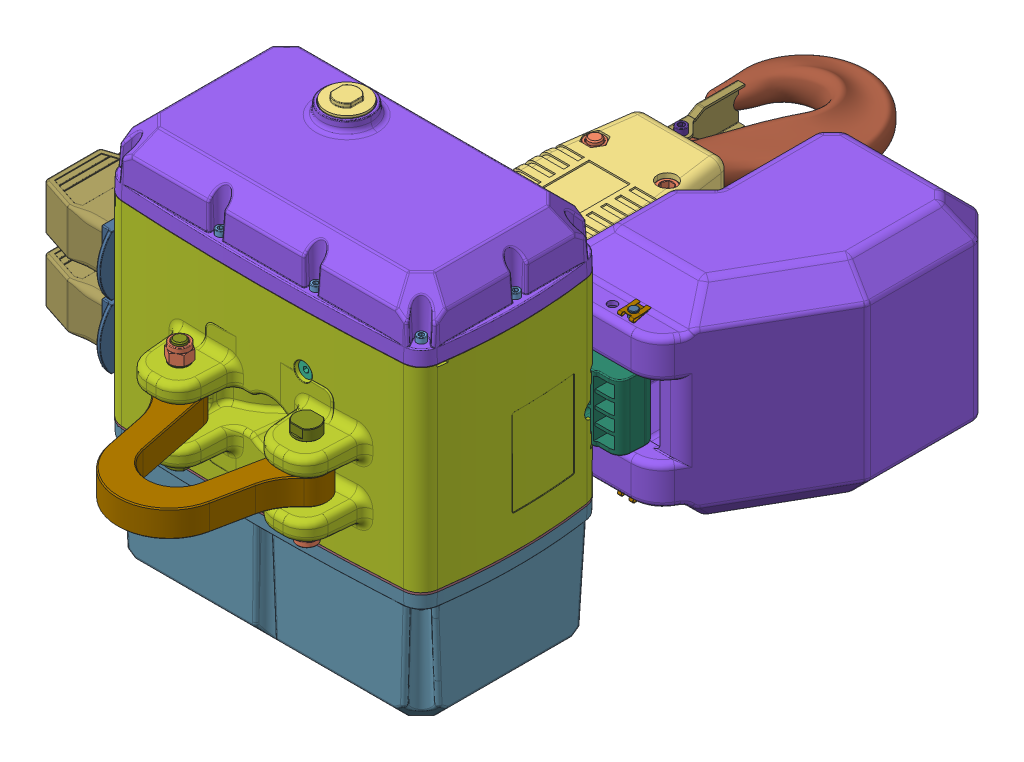
SolidWorks assembly NCH2072-2000kg, configuration 默认. Lengths in mm.
Overall size (525.49 383 710.03).
102 component instances, 45 part files, 0 mates.
Components (placement in the parent):
- N120411-0000018_A-1: N120411-0000018_A [默认] at origin size (432.61 383 254.47)
  - N120411-0000038_A-1: N120411-0000038_A [默认] at (227 0 0) x (-1 0 0) z (0 0 1) size (312 295.03 232.39)
    - N010122-0000197_A-2-1: N010122-0000197_A-2 [默认] at (207 -124.7 87.75) x (1 0 0) z (0 -1 0) size (8.5 8.5 30.21)
    - N010122-0000197_A-2-2: N010122-0000197_A-2 [默认] at (25 -124.7 -65.75) x (0 0 -1) z (0 -1 0) size (8.5 8.5 30.21)
    - N010122-0000197_A-2-3: N010122-0000197_A-2 [默认] at (25 -124.7 95.25) x (0 0 -1) z (0 -1 0) size (8.5 8.5 30.21)
    - N010122-0000197_A-2-4: N010122-0000197_A-2 [默认] at (-67 -124.7 -58.25) x (1 0 0) z (0 -1 0) size (8.5 8.5 30.21)
    - N010122-0000197_A-2-5: N010122-0000197_A-2 [默认] at (-67 -124.7 87.75) x (-1 0 0) z (0 -1 0) size (8.5 8.5 30.21)
    - N010122-0000197_A-2-6: N010122-0000197_A-2 [默认] at (207 -124.7 -58.25) x (0 0 -1) z (0 -1 0) size (8.5 8.5 30.21)
    - N010122-0000197_A-2-7: N010122-0000197_A-2 [默认] at (115 -124.7 -65.75) x (0 0 -1) z (0 -1 0) size (8.5 8.5 30.21)
    - N010122-0000197_A-2-8: N010122-0000197_A-2 [默认] at (-75 -124.7 7.0181) x (0 0 -1) z (0 -1 0) size (8.5 8.5 30.21)
    - N010122-0000197_A-2-9: N010122-0000197_A-2 [默认] at (215 -124.7 7.05) x (-1 0 0) z (0 -1 0) size (8.5 8.5 30.21)
    - N010122-0000197_A-2-10: N010122-0000197_A-2 [默认] at (115 -124.7 95.25) x (0 0 -1) z (0 -1 0) size (8.5 8.5 30.21)
    - N090501-0000042-1: N090501-0000042 [默认] at (70 -110.2 14.75) x (1 0 0) z (0 -1 0) size (310 180 0.5)
    - N090501-0000029-2-1: N090501-0000029-2 [默认] at (109.28 -179.2 -18.11) x (0 0 -1) z (1 0 0) size (39 14 39)
    - N090501-0000045-1: N090501-0000045 [默认] at (0 0 6.75) x (0 0 -1) z (1 0 0) size (51.5 30.1 103)
    - N090501-0000034-2-1: N090501-0000034-2 [默认] at (133 0 104.75) x (0 0 -1) z (-1 0 0) size (9 16 16)
    - N090501-0000034-2-2: N090501-0000034-2 [默认] at (133 55 104.75) x (0 0 -1) z (-1 0 0) size (9 16 16)
    - N010153-0000021-2-1: N010153-0000021-2 [默认] at (28 -60.2 96.65) x (0 0 -1) z (0.999621 -0.02754 0) size (11 14 14)
    - N090501-0000040-1: N090501-0000040 [默认] at (0 -96.2 6.75) x (1 0 0) z (0 -1 0) size (312 232.39 220.06)
    - N090501-0000041-1: N090501-0000041 [默认] at (70 -110.7 14.75) x (1 0 0) z (0 -1 0) size (310 180 68.75)
  - N120411-0000037_A-2-1: N120411-0000037_A-2 [默认] at (-13.5 19.2 24.25) x (0 0 -1) z (-1 0 0) size (115.15 58 102.79)
    - N080101-0000427-2-1: N080101-0000427-2 [默认] at (0 0 -13.5) x (-1 0 0) z (0 0 1) size (93 58 27)
    - N080101-0000426-2-1: N080101-0000426-2 [默认] at (-14 0 13.5) x (-1 0 0) z (0 1 0) size (48.06 27 56.06)
    - N080101-0000426-2-2: N080101-0000426-2 [默认] at (14 0 13.5) x (1 0 0) z (0 -1 0) size (48.06 27 56.06)
    - N080101-0000428-2-1: N080101-0000428-2 [默认] at (23.1007 0 65.4698) x (0.950157 0 0.31177) z (0.31177 0 -0.950157) size (35 33.1 27.16)
    - N080101-0000430-2-1: N080101-0000430-2 [默认] at (0.0003 0 33.5003) x (0 0 1) z (0 -1 0) size (75 73.68 56)
  - N120411-0000037_A-2-2: N120411-0000037_A-2 [默认] at (-13.5 -40.8 24.25) x (0 0 -1) z (-1 0 0) size (115.15 58 102.79)
    - N080101-0000427-2-1: N080101-0000427-2 [默认] at (0 0 -13.5) x (-1 0 0) z (0 0 1) size (93 58 27)
    - N080101-0000426-2-1: N080101-0000426-2 [默认] at (-14 0 13.5) x (-1 0 0) z (0 1 0) size (48.06 27 56.06)
    - N080101-0000426-2-2: N080101-0000426-2 [默认] at (14 0 13.5) x (1 0 0) z (0 -1 0) size (48.06 27 56.06)
    - N080101-0000428-2-1: N080101-0000428-2 [默认] at (23.1007 0 65.4698) x (0.950157 0 0.31177) z (0.31177 0 -0.950157) size (35 33.1 27.16)
    - N080101-0000430-2-1: N080101-0000430-2 [默认] at (0.0003 0 33.5003) x (0 0 1) z (0 -1 0) size (75 73.68 56)
  - N090501-0000044-1: N090501-0000044 [默认] at (157 -75.8 14.75) x (1 0 0) z (0 1 0) size (310 180 8)
  - N090501-0000043-1: N090501-0000043 [默认] at (157 -75.8 14.75) x (-1 0 0) z (0 1 0) size (310 180.63 122.55)
  - N090501-0000046-1: N090501-0000046 [默认] at (238.4113 0 -68.99) x (0 1 0) z (0 0 -1) size (62.8 182.79 104.72)
  - N090501-0000047-1: N090501-0000047 [默认] at (107 -47.25 128.75) x (-1 0 0) z (0 1 0) size (23.09 23.09 101)
  - N090501-0000047-2: N090501-0000047 [默认] at (227 47.25 128.75) x (0 0 -1) z (0 -1 0) size (23.09 23.09 101)
  - N080101-0000401-2-1: N080101-0000401-2 [默认] at (272.5252 -24.94 -81.04) x (1 0 0) z (0 1 0) size (20 18.9 6.45)
  - N080101-0000401-2-2: N080101-0000401-2 [默认] at (191.7884 -24.94 -70.94) x (1 0 0) z (0 1 0) size (20 18.9 6.45)
  - N010302-0000058-2-1: N010302-0000058-2 [默认] at (186.8531 -16.9523 -71.84) x (0 -1 0) z (-0.268551 0 0.963266) size (14 2.5 2.5)
  - N010302-0000058-2-2: N010302-0000058-2 [默认] at (277.2152 -16.9784 -81.94) x (0 -1 0) z (-0.268551 0 0.963266) size (14 2.5 2.5)
  - N010302-0000058-2-3: N010302-0000058-2 [默认] at (267.5899 -16.9523 -81.94) x (0 -1 0) z (-0.268551 0 0.963266) size (14 2.5 2.5)
  - N010302-0000058-2-4: N010302-0000058-2 [默认] at (196.4784 -16.9784 -71.84) x (0 -1 0) z (-0.268551 0 0.963266) size (14 2.5 2.5)
  - Washer_GBIT_95_2002_5.0_v12.00-1: Washer_GBIT_95_2002_5.0_v12.00 [默认] at (294.4484 24.24 -82.445) x (0 -1 0) z (0 0 -1) size (10 10 1)
  - Washer_GBIT_95_2002_5.0_v12.00-2: Washer_GBIT_95_2002_5.0_v12.00 [默认] at (294.4484 -24.24 -82.445) x (-1 0 0) z (0 0 -1) size (10 10 1)
  - Nut_GBIT_889.1_2000_M12_v12.00-1: Nut_GBIT_889.1_2000_M12_v12.00 [默认] at (227 -36.75 128.75) x (0 0 -1) z (0 -1 0) size (20.78 18 14.9)
  - Nut_GBIT_889.1_2000_M12_v12.00-2: Nut_GBIT_889.1_2000_M12_v12.00 [默认] at (107 36.75 128.75) x (0 0 1) z (0 1 0) size (20.78 18 14.9)
  - Washer_GBIT_96_1985_6.0_v12.00-2-1: Washer_GBIT_96_1985_6.0_v12.00-2 [默认] at (8.5 19.2 -58.25) x (0 1 0) z (-1 0 0) size (18 18 1.6)
  - N010122-0000201-2-1: N010122-0000201-2 [默认] at (294.4484 24.24 -83.445) x (0 0 1) z (1 0 0) size (35 8.5 8.5)
  - N010122-0000201-2-2: N010122-0000201-2 [默认] at (294.4484 -24.24 -83.445) x (0 0 1) z (1 0 0) size (35 8.5 8.5)
  - N010108-0000011-2-1: N010108-0000011-2 [默认] at (7 -24.8 -17.25) x (0 0 1) z (0 -1 0) size (7 15.13 7)
  - N010108-0000011-2-2: N010108-0000011-2 [默认] at (7 -24.8 65.75) x (0 0 1) z (0 -1 0) size (7 15.13 7)
  - N010108-0000011-2-3: N010108-0000011-2 [默认] at (7 -56.8 65.75) x (0 0 1) z (0 -1 0) size (7 15.13 7)
  - N010108-0000011-2-4: N010108-0000011-2 [默认] at (7 35.2 -17.25) x (0 0 1) z (0 -1 0) size (7 15.13 7)
  - N010108-0000011-2-5: N010108-0000011-2 [默认] at (7 35.2 65.75) x (0 0 1) z (0 -1 0) size (7 15.13 7)
  - N010108-0000011-2-6: N010108-0000011-2 [默认] at (7 -56.8 -17.25) x (0 0 1) z (0 -1 0) size (7 15.13 7)
  - N010108-0000011-2-7: N010108-0000011-2 [默认] at (7 3.2 65.75) x (0 0 1) z (0 -1 0) size (7 15.13 7)
  - N010108-0000011-2-8: N010108-0000011-2 [默认] at (7 3.2 -17.25) x (0 0 1) z (0 -1 0) size (7 15.13 7)
  - N010122-0000129_A-2-1: N010122-0000129_A-2 [默认] at (6.9 19.2 -58.25) x (0 -1 0) z (-1 0 0) size (10 10 16.26)
  - N010122-0000197_A-2-1: N010122-0000197_A-2 [默认] at (20 -87.8 -58.25) x (0 0 -1) z (0 -1 0) size (8.5 8.5 30.21)
  - N010122-0000197_A-2-2: N010122-0000197_A-2 [默认] at (20 -87.8 87.75) x (0 0 -1) z (0 -1 0) size (8.5 8.5 30.21)
  - N010122-0000197_A-2-3: N010122-0000197_A-2 [默认] at (294 -87.8 -58.25) x (1 0 0) z (0 -1 0) size (8.5 8.5 30.21)
  - N010122-0000197_A-2-4: N010122-0000197_A-2 [默认] at (157 -87.8 95.25) x (1 0 0) z (0 -1 0) size (8.5 8.5 30.21)
  - N010122-0000197_A-2-5: N010122-0000197_A-2 [默认] at (294 -87.8 87.75) x (0 0 1) z (0 -1 0) size (8.5 8.5 30.21)
  - N010122-0000197_A-2-6: N010122-0000197_A-2 [默认] at (157 -87.8 -65.75) x (1 0 0) z (0 -1 0) size (8.5 8.5 30.21)
  - N010122-0000126_A-1: N010122-0000126_A [默认] at (161.1284 22.22 -70.325) x (0 1 0) z (0 0 -1) size (13 13 28.31)
  - N010122-0000126_A-2: N010122-0000126_A [默认] at (161 -22 -70.325) x (1 0 0) z (0 0 -1) size (13 13 28.31)
  - N010122-0000126_A-3: N010122-0000126_A [默认] at (227 -22 -70.325) x (1 0 0) z (0 0 -1) size (13 13 28.31)
  - N010122-0000126_A-4: N010122-0000126_A [默认] at (227 22 -70.325) x (-1 0 0) z (0 0 -1) size (13 13 28.31)
- N120411-0000016_A-2-1: N120411-0000016_A-2 [默认] at (373.6984 0 -85.99) x (-1 0 0) z (0 0 1) size (185.31 195 260)
  - N090501-0000036-2-1: N090501-0000036-2 [默认] at (71 0 0) x (-1 0 0) z (0 1 0) size (185.31 260 195)
  - N090501-0000038-2-1: N090501-0000038-2 [默认] at (46.6851 -75.6871 -10.4095) x (-1 0 0) z (0 0.965926 -0.258819) size (14.5 17.8 5.58)
  - N090501-0000038-2-2: N090501-0000038-2 [默认] at (46.6855 74.5267 -10.5201) x (-1 -0.000657 -0.000063) z (-0.000651 0.997424 -0.07173) size (14.5 17.8 5.58)
  - N090501-0000037-2-1: N090501-0000037-2 [默认] at (54 -0.0009 -1) x (0 1 0) z (-1 0 0) size (153 8 8)
- N120411-0000015_A-1: N120411-0000015_A [默认] at (157.4321 0 -397.1437) x (-1 0 0) z (0 0 1) size (126.51 77.97 311.14)
  - N120411-0000014_A-1: N120411-0000014_A [默认] at origin size (125.89 53 211.64)
    - N090501-0000060_A-1: N090501-0000060_A [默认] x (-1 0 0) z (0 1 0) size (125.89 211.64 38.35)
    - N080101-0000412-1: N080101-0000412 [默认] at (35 0 13) x (0 -1 0) z (-1 0 0) size (36 72 20.07)
    - N080101-0000413-1: N080101-0000413 [默认] at (23 0 80) x (0 1 0) z (0.88478 0 -0.466009) size (19.71 23.55 21.02)
    - N090501-0000058-1: N090501-0000058 [默认] at (0 0 138) x (0 -1 0) z (0 0 -1) size (22.5 45 22)
    - N090501-0000058-2: N090501-0000058 [默认] at (0 0 138) x (0 1 0) z (0 0 -1) size (22.5 45 22)
    - N010212-0000004-1: N010212-0000004 [默认] at (0 0 124) x (0 0 1) z (0 1 0) size (16 52 52)
    - Nut_GBIT_889.1_2000_M6_v12.00-1: Nut_GBIT_889.1_2000_M6_v12.00 [默认] at (23 13 80) x (1 0 0) z (0 1 0) size (11.55 10 8)
    - N010122-0000128_A-1: N010122-0000128_A [默认] at (23 -13 80) x (1 0 0) z (0 -1 0) size (10 10 46.26)
  - Nut_GBIT_889.1_2000_M12_v12.00-1: Nut_GBIT_889.1_2000_M12_v12.00 [默认] at (-34 21.0145 150.5) x (1 0 0) z (0 1 0) size (20.78 18 14.9)
  - Nut_GBIT_889.1_2000_M12_v12.00-2: Nut_GBIT_889.1_2000_M12_v12.00 [默认] at (34 -21.0145 150.5) x (1 0 0) z (0 -1 0) size (20.78 18 14.9)
  - N090501-0000059-1: N090501-0000059 [默认] at (0 -13.5145 200.5784) x (0 0 1) z (0 1 0) size (63.61 60.5 58)
  - N010202-0000007-1: N010202-0000007 [默认] at (0 -22.0145 200.5784) x (0 -1 0) z (-1 0 0) size (14 47 47)
  - N010202-0000007-2: N010202-0000007 [默认] at (0 22.0145 200.5784) x (0 1 0) z (1 0 0) size (14 47 47)
  - N010122-0000151_A-1: N010122-0000151_A [默认] at (-34 -21.0145 150.5) x (1 0 0) z (0 -1 0) size (18 18 72.51)
  - N010122-0000151_A-2: N010122-0000151_A [默认] at (34 21.0145 150.5) x (1 0 0) z (0 1 0) size (18 18 72.51)
  - N090501-0000056-1: N090501-0000056 [默认] at (0 37.0145 100.5) x (1 0 0) z (0 -1 0) size (107 145 37)
  - N090501-0000056-2: N090501-0000056 [默认] at (0 -37.0145 100.5) x (-1 0 0) z (0 1 0) size (107 145 37)
- N090501-0000022-1-1: N090501-0000022-1 [默认] at (270.3013 0 -153.4413) x (0 -1 0) z (-1 0 0) size (32.86 57.06 32.85)
- N090501-0000022-1-2: N090501-0000022-1 [默认] at (191.6427 0 -124.1437) x (0 -1 0) z (-1 0 0) size (32.86 57.06 32.85)
- N090501-0000055-1: N090501-0000055 [默认] at (191.5836 0 -92.6437) x (0 0 -1) z (0 -1 0) size (24.5 51 51)
- N090501-0000055-2: N090501-0000055 [默认] at (269.7929 1.2458 -114.9915) x (0 0 -1) z (0 -1 0) size (24.5 51 51)
- N090501-0000062-1: N090501-0000062 [默认] at (158.9997 0 -60.75) x (1 0 0) z (0 0 -1) size (40 10 10)
- N080101-0000400-1-1: N080101-0000400-1 [默认] at (278.1975 0 -194.505) x (0 -1 0) z (1 0 0) size (44.63 53 14)
- N080101-0000400-1-2: N080101-0000400-1 [默认] at (281.7622 0 -194.505) x (0 1 0) z (-1 0 0) size (44.63 53 14)
- N080101-0000414-1: N080101-0000414 [默认] at (90.2045 -0.0131 126.1643) x (-1 0 0) z (0 1 0) size (91.6 240.14 24.02)
- N090501-0000091-1: N090501-0000091 [默认] at (167 0.75 128.75) x (1 0 0) z (0 -1 0) size (158 137.5 25)
